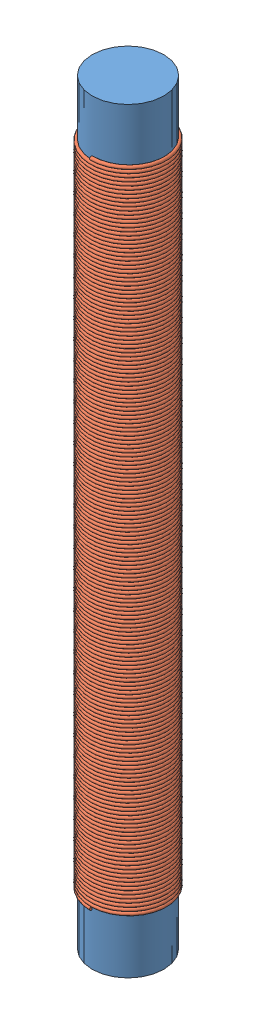
SolidWorks assembly Rod_Spiral_Assembly, configuration Default. Lengths in mm.
Overall size (8.7 71 7.53).
2 component instances, 2 part files, 3 mates.
Components (placement in the parent):
- TorqueRod-1: TorqueRod [Default] at origin size (6.73 71 6.73)
- RodSpiral-1: RodSpiral [Default] at (0 66 0) x (0 0 1) z (0 -1 0) size (7.53 8.7 61.32)
Mates (geometry in assembly coordinates):
- Coincident1: coincident anti-aligned: plane of TorqueRod-1 through (0 0 0) normal (1 0 0); plane of RodSpiral-1 through (0 66 0) normal (-1 0 0)
- Coincident2: coincident aligned: plane of TorqueRod-1 through (0 0 0) normal (0 0 1); plane of RodSpiral-1 through (0 66 0) normal (0 0 1)
- Distance1: distance = 5 mm anti-aligned: plane of RodSpiral-1 through (0 66 0) normal (0 -1 0); plane of TorqueRod-1 through (0 71 0) normal (0 1 0)
